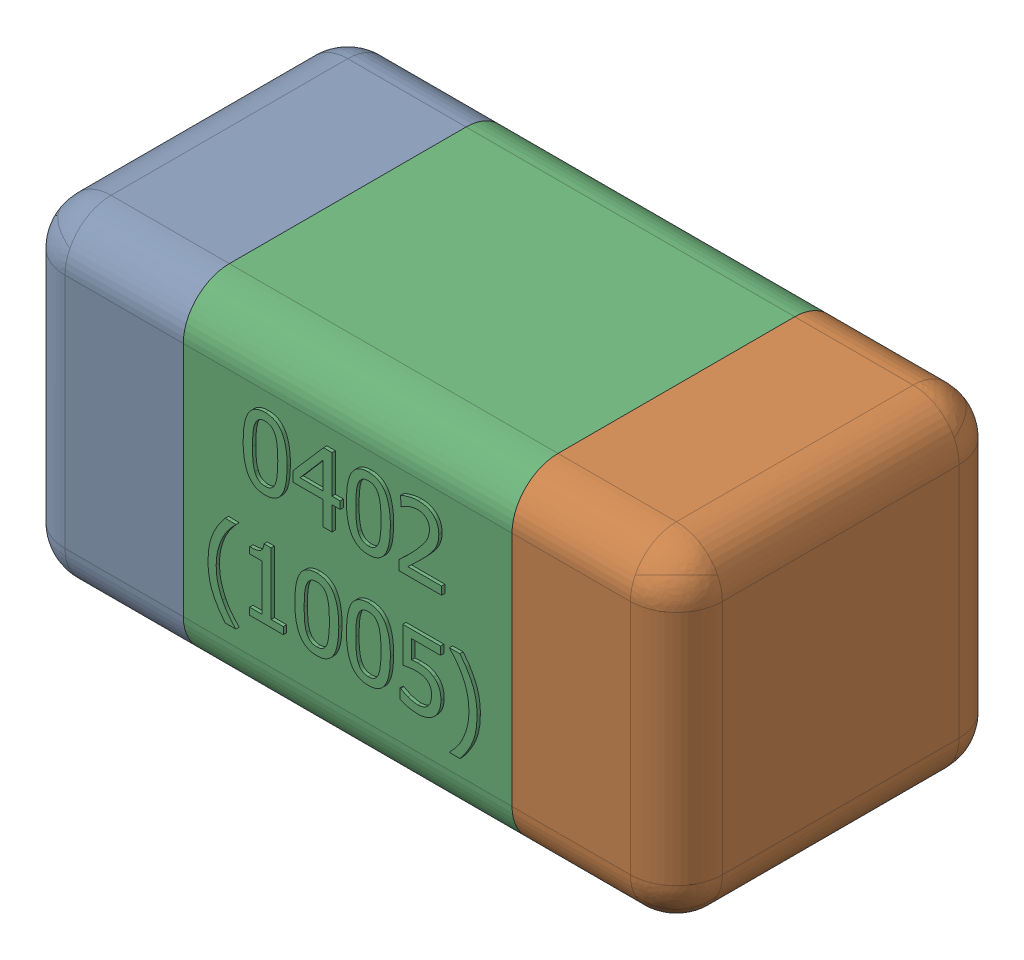
SolidWorks assembly C47, configuration Standard. Lengths in mm.
Overall size (1.01 0.51 0.51).
4 component instances, 3 part files, 0 mates.
Components (placement in the parent):
- C47-subassembly-1-1: C47-subassembly-1 [Standard] at (5.3001 10.9 0) x (1 0 0) z (0 0 1) size (1.01 0.51 0.51)
  - User Library-0402_Cap-1: User Library-0402_Cap [Standard] at origin size (0.26 0.51 0.51)
  - User Library-0402_Cap-1-1: User Library-0402_Cap-1 [Standard] at origin size (0.26 0.5 0.51)
  - User Library-0402_Cap-2-1: User Library-0402_Cap-2 [Standard] at origin size (0.5 0.5 0.51)
